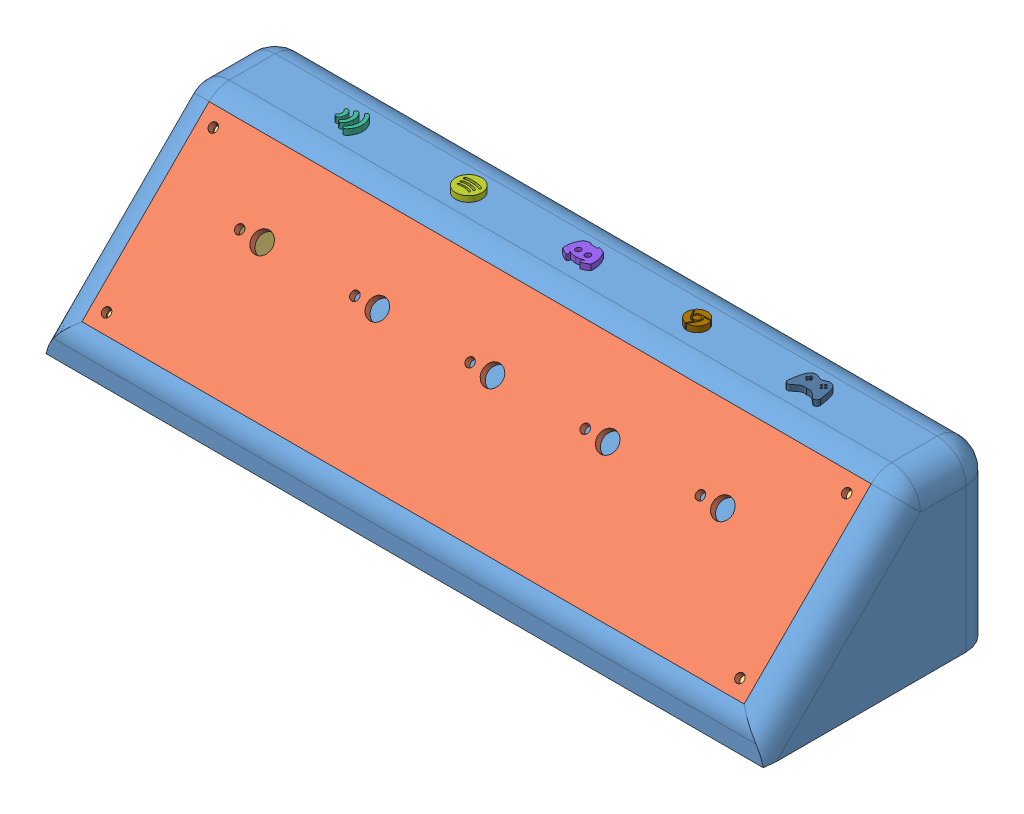
SolidWorks assembly Master, configuration Default. Lengths in mm.
Overall size (250 62 80).
11 component instances, 10 part files, 16 mates.
Components (placement in the parent):
- Baseplate-1: Baseplate [Default] at (114.4791 108.7869 195.4571) size (250 60 80)
- Faceplate-1: Faceplate [Default] at (-0.5209 119.9455 230.7629) x (1 0 0) z (0 0.707107 0.707107) size (230 62.43 2.5)
- Supports-1: Supports [Default] at (219.4791 113.7869 160.4571) size (15 45 70)
- Supports-2: Supports [Default] at (-5.5209 113.7869 160.4571) size (15 45 70)
- Backplate-1: Backplate [Default] at (-0.5209 113.7869 155.4571) size (230 45 5)
- ArduinoSupport-1: ArduinoSupport [Default] at (114.7427 116.7869 186.0906) x (-0.999963 0 0.008556) z (0 -1 0) size (16.76 44.7 3)
- MasterVolumeLogo-1: MasterVolumeLogo [Default] at (29.3213 168.7869 178.6756) size (8.01 2 8.75)
- Spotify logo-1: Spotify logo [Default] at (69.7933 168.7869 177.9962) x (1 0 -0.000252) z (0.000252 0 1) size (9.02 2 9.02)
- Discord-Logo-1: Discord-Logo [Default] at (106.6999 168.7869 178.3086) size (10.14 2 7.68)
- GoogleChromeLogo-1: GoogleChromeLogo [Default] at (149.6728 168.7869 177.9505) size (7.69 2 7.7)
- ControllerLogo-1: ControllerLogo [Default] at (184.8273 168.7869 178.8362) size (11.4 2 8.08)
Mates (geometry in assembly coordinates):
- Coincident3: coincident aligned: line of Baseplate-1 through (229.4791 165.8579 188.386) axis (-1 0 0); line of Faceplate-1 through (229.4791 165.8579 188.386) axis (-1 0 0)
- Coincident4: coincident aligned: line of Baseplate-1 through (-0.5209 165.8579 188.386) axis (0 -0.707107 0.707107); line of Faceplate-1 through (-0.5209 165.8579 188.386) axis (0 -0.707107 0.707107)
- Coincident5: coincident anti-aligned: plane of Baseplate-1 through (114.4791 113.7869 195.4571) normal (0 1 0); plane of Supports-1 through (219.4791 113.7869 235.4571) normal (0 -1 0)
- Coincident6: coincident anti-aligned: plane of Baseplate-1 through (234.4791 168.7869 235.4571) normal (-1 0 0); plane of Supports-1 through (234.4791 113.7869 235.4571) normal (1 0 0)
- Coincident7: coincident: line of Baseplate-1 through (229.4791 158.7869 160.4571) axis (0 -1 0); plane of Supports-1 through (219.4791 113.7869 160.4571) normal (0 0 -1)
- Coincident8: coincident anti-aligned: plane of Baseplate-1 through (-5.5209 168.7869 235.4571) normal (1 0 0); plane of Supports-2 through (-5.5209 113.7869 235.4571) normal (-1 0 0)
- Coincident9: coincident anti-aligned: plane of Baseplate-1 through (114.4791 113.7869 195.4571) normal (0 1 0); plane of Supports-2 through (-5.5209 113.7869 235.4571) normal (0 -1 0)
- Coincident10: coincident: line of Baseplate-1 through (-0.5209 113.7869 160.4571) axis (0 1 0); plane of Supports-2 through (-5.5209 113.7869 160.4571) normal (0 0 -1)
- Coincident11: coincident anti-aligned: line of Baseplate-1 through (-0.5209 158.7869 155.4571) axis (1 0 0); line of Backplate-1 through (229.4791 158.7869 155.4571) axis (-1 0 0)
- Coincident12: coincident anti-aligned: line of Baseplate-1 through (229.4791 158.7869 155.4571) axis (0 -1 0); line of Backplate-1 through (229.4791 113.7869 155.4571) axis (0 1 0)
- Coincident14: coincident anti-aligned: plane of Baseplate-1 through (114.4791 113.7869 195.4571) normal (0 1 0); plane of ArduinoSupport-1 through (122.5471 113.7869 207.6146) normal (0 -1 0)
- Coincident15: coincident anti-aligned: plane of Baseplate-1 through (114.4791 168.7869 195.4571) normal (0 1 0); plane of MasterVolumeLogo-1 through (36.3829 168.7869 175.5041) normal (0 -1 0)
- Coincident16: coincident anti-aligned: plane of Baseplate-1 through (114.4791 168.7869 195.4571) normal (0 1 0); plane of Spotify logo-1 through (74.6393 168.7869 173.3595) normal (0 -1 0)
- Coincident17: coincident anti-aligned: plane of Baseplate-1 through (114.4791 168.7869 195.4571) normal (0 1 0); plane of Discord-Logo-1 through (106.6999 168.7869 178.3086) normal (0 -1 0)
- Coincident18: coincident anti-aligned: plane of Baseplate-1 through (114.4791 168.7869 195.4571) normal (0 1 0); plane of GoogleChromeLogo-1 through (154.1665 168.7869 173.5733) normal (0 -1 0)
- Coincident19: coincident anti-aligned: plane of Baseplate-1 through (114.4791 168.7869 195.4571) normal (0 1 0); plane of ControllerLogo-1 through (195.7794 168.7869 170.1542) normal (0 -1 0)
